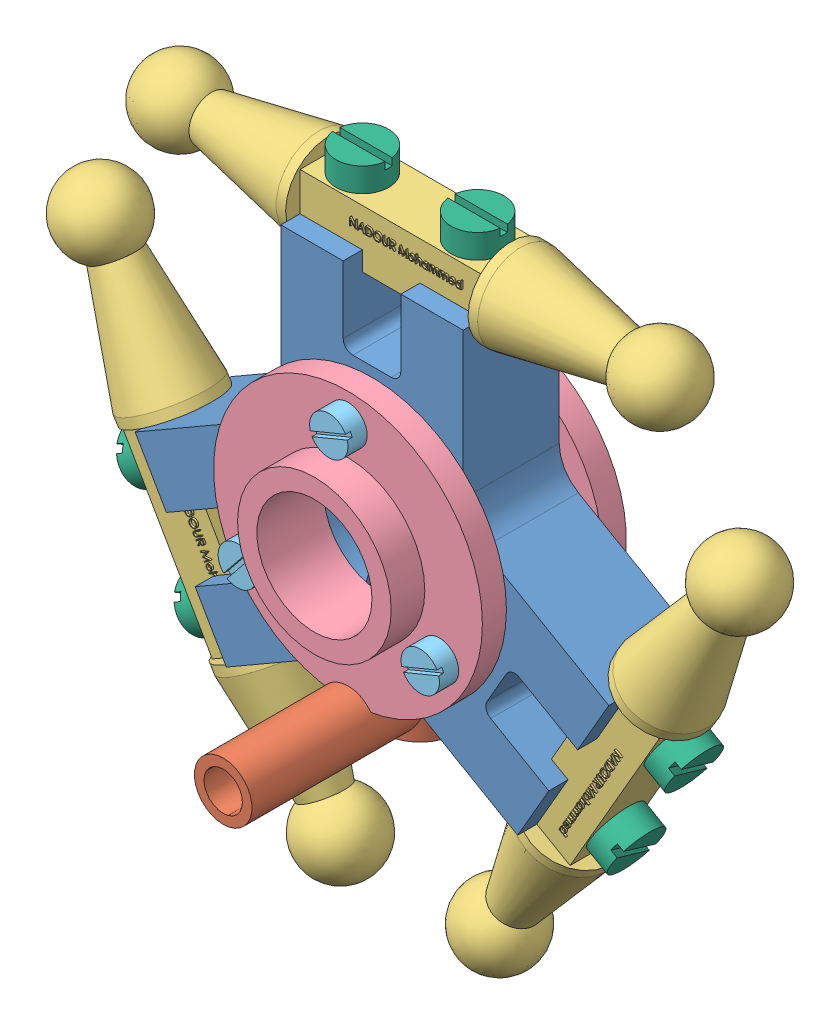
SolidWorks assembly Nacelle1, configuration Défaut. Lengths in mm.
Overall size (78.36 68.86 31.5).
19 component instances, 6 part files, 41 mates.
Components (placement in the parent):
- Pièce5_Nacelle-1: Pièce5_Nacelle [Défaut] at origin size (49.34 42.73 10)
- Pièce5_RaccordTuyau-1: Pièce5_RaccordTuyau [Défaut] at (0 -16.5885 0) x (1 0 0) z (0 1 0) size (8 24.5 10)
- Pièce2_Articulation-1: Pièce2_Articulation [Défaut] at (0 24 0) size (58 9 9)
- Pièce2_Articulation-2: Pièce2_Articulation [Défaut] at (-20.7846 -12 0) x (0.5 -0.866025 0) z (0 0 1) size (58 9 9)
- Pièce2_Articulation-3: Pièce2_Articulation [Défaut] at (20.7846 -12 0) x (-0.5 -0.866025 0) z (0 0 1) size (58 9 9)
- Pièce5_Capot-1: Pièce5_Capot [Défaut] at (0 0 11) x (-1 0 0) z (0 0 -1) size (28 28 7)
- Pièce5_Capot-2: Pièce5_Capot [Défaut] at (0 0 -11) size (28 28 7)
- Pièce5_ViceTcyM2.5_10-4: Pièce5_ViceTcyM2.5_10 [Défaut] at (0 11 -9.5) size (4 4 9.5)
- Pièce5_ViceTcyM2.5_10-5: Pièce5_ViceTcyM2.5_10 [Défaut] at (-9.5263 -5.5 -9.5) size (4 4 9.5)
- Pièce5_ViceTcyM2.5_10-6: Pièce5_ViceTcyM2.5_10 [Défaut] at (9.5263 -5.5 -9.5) size (4 4 9.5)
- Pièce5_ViceTcyM3_10-1: Pièce5_ViceTcyM3_10 [Défaut] at (-6 29.5 0) x (1 0 0) z (0 -1 0) size (5.5 5.5 12.5)
- Pièce5_ViceTcyM3_10-2: Pièce5_ViceTcyM3_10 [Défaut] at (6 29.5 0) x (1 0 0) z (0 -1 0) size (5.5 5.5 12.5)
- Pièce5_ViceTcyM3_10-3: Pièce5_ViceTcyM3_10 [Défaut] at (28.5477 -9.5538 0) x (0.25 0.433013 0.866025) z (-0.866025 0.5 0) size (5.5 5.5 12.5)
- Pièce5_ViceTcyM3_10-4: Pièce5_ViceTcyM3_10 [Défaut] at (22.5477 -19.9462 0) x (0.25 0.433013 0.866025) z (-0.866025 0.5 0) size (5.5 5.5 12.5)
- Pièce5_ViceTcyM3_10-5: Pièce5_ViceTcyM3_10 [Défaut] at (-28.5477 -9.5538 0) x (0.25 -0.433013 -0.866025) z (0.866025 0.5 0) size (5.5 5.5 12.5)
- Pièce5_ViceTcyM3_10-6: Pièce5_ViceTcyM3_10 [Défaut] at (-22.5477 -19.9462 0) x (0.25 -0.433013 -0.866025) z (0.866025 0.5 0) size (5.5 5.5 12.5)
- Pièce5_ViceTcyM2.5_10-7: Pièce5_ViceTcyM2.5_10 [Défaut] at (9.5263 -5.5 9.5) x (-0.923728 -0.383049 0) z (0 0 -1) size (4 4 9.5)
- Pièce5_ViceTcyM2.5_10-8: Pièce5_ViceTcyM2.5_10 [Défaut] at (0 11 9.5) x (-0.923728 -0.383049 0) z (0 0 -1) size (4 4 9.5)
- Pièce5_ViceTcyM2.5_10-9: Pièce5_ViceTcyM2.5_10 [Défaut] at (-9.5263 -5.5 9.5) x (-0.627519 -0.778601 0) z (0 0 -1) size (4 4 9.5)
Mates (geometry in assembly coordinates):
- Coaxiale1: concentric aligned: cylinder of Pièce5_Nacelle-1 through (0 -18 0) axis (0 1 0) radius 4; cylinder of Pièce5_RaccordTuyau-1 through (0 -18.5885 0) axis (0 1 0) radius 4
- Coaxiale5: concentric anti-aligned: cylinder of Pièce5_Nacelle-1 through (0 -15.5885 -5) axis (0 0 1) radius 4; cylinder of Pièce5_RaccordTuyau-1 through (0 -15.5885 20.5) axis (0 0 -1) radius 3
- Coaxiale6: concentric aligned: cylinder of Pièce5_Nacelle-1 through (-6 16 0) axis (0 1 0) radius 1; cylinder of Pièce2_Articulation-1 through (-6 17.5 0) axis (0 1 0) radius 1.6
- Coaxiale7: concentric aligned: cylinder of Pièce5_Nacelle-1 through (6 16 0) axis (0 1 0) radius 1; cylinder of Pièce2_Articulation-1 through (6 17.5 0) axis (0 1 0) radius 1.6
- Coïncidente1: coincident anti-aligned: plane of Pièce5_Nacelle-1 through (9.5 21 -3) normal (0 1 0); plane of Pièce2_Articulation-1 through (-9.5 21 -3) normal (0 -1 0)
- Coaxiale8: concentric anti-aligned: cylinder of Pièce5_Nacelle-1 through (-10.8564 -13.1962 0) axis (-0.866025 -0.5 0) radius 1; cylinder of Pièce2_Articulation-2 through (-23.4138 -20.4462 0) axis (0.866025 0.5 0) radius 1.6
- Coaxiale9: concentric anti-aligned: cylinder of Pièce5_Nacelle-1 through (-16.8564 -2.8038 0) axis (-0.866025 -0.5 0) radius 1; cylinder of Pièce2_Articulation-2 through (-29.4138 -10.0538 0) axis (0.866025 0.5 0) radius 1.6
- Coïncidente2: coincident anti-aligned: plane of Pièce5_Nacelle-1 through (-22.9365 -2.2728 -3) normal (-0.866025 -0.5 0); plane of Pièce2_Articulation-2 through (-22.9365 -2.2728 -3) normal (0.866025 0.5 0)
- Coaxiale10: concentric aligned: cylinder of Pièce5_Nacelle-1 through (10.8564 -13.1962 0) axis (0.866025 -0.5 0) radius 1; cylinder of Pièce2_Articulation-3 through (12.1554 -13.9462 0) axis (0.866025 -0.5 0) radius 1.6
- Coaxiale11: concentric aligned: cylinder of Pièce5_Nacelle-1 through (16.8564 -2.8038 0) axis (0.866025 -0.5 0) radius 1; cylinder of Pièce2_Articulation-3 through (18.1554 -3.5538 0) axis (0.866025 -0.5 0) radius 1.6
- Coïncidente3: coincident anti-aligned: plane of Pièce5_Nacelle-1 through (13.4365 -18.7272 -3) normal (0.866025 -0.5 0); plane of Pièce2_Articulation-3 through (22.9365 -2.2728 -3) normal (-0.866025 0.5 0)
- Coaxiale12: concentric aligned: cylinder of Pièce2_Articulation-1 through (6 17.5 0) axis (0 1 0) radius 1.6; cylinder of Pièce5_ViceTcyM3_10-2 through (6 17 0) axis (0 1 0) radius 1.5
- Coaxiale13: concentric aligned: cylinder of Pièce2_Articulation-1 through (-6 17.5 0) axis (0 1 0) radius 1.6; cylinder of Pièce5_ViceTcyM3_10-1 through (-6 17 0) axis (0 1 0) radius 1.5
- Coaxiale14: concentric aligned: cylinder of Pièce2_Articulation-3 through (18.1554 -3.5538 0) axis (0.866025 -0.5 0) radius 1.6; cylinder of Pièce5_ViceTcyM3_10-3 through (17.7224 -3.3038 0) axis (0.866025 -0.5 0) radius 1.5
- Coaxiale15: concentric aligned: cylinder of Pièce2_Articulation-3 through (12.1554 -13.9462 0) axis (0.866025 -0.5 0) radius 1.6; cylinder of Pièce5_ViceTcyM3_10-4 through (11.7224 -13.6962 0) axis (0.866025 -0.5 0) radius 1.5
- Coaxiale19: concentric aligned: cylinder of Pièce5_Capot-2 through (0 11 -3) axis (0 0 -1) radius 1.3; cylinder of Pièce5_ViceTcyM2.5_10-4 through (0 11 0) axis (0 0 -1) radius 1.3
- Coaxiale20: concentric aligned: cylinder of Pièce5_Capot-2 through (-9.5263 -5.5 -3) axis (0 0 -1) radius 1.3; cylinder of Pièce5_ViceTcyM2.5_10-5 through (-9.5263 -5.5 0) axis (0 0 -1) radius 1.3
- Coaxiale21: concentric aligned: cylinder of Pièce5_Capot-2 through (9.5263 -5.5 -3) axis (0 0 -1) radius 1.3; cylinder of Pièce5_ViceTcyM2.5_10-6 through (9.5263 -5.5 0) axis (0 0 -1) radius 1.3
- Coaxiale22: concentric anti-aligned: cylinder of Pièce2_Articulation-2 through (-29.4138 -10.0538 0) axis (0.866025 0.5 0) radius 1.6; cylinder of Pièce5_ViceTcyM3_10-5 through (-17.7224 -3.3038 0) axis (-0.866025 -0.5 0) radius 1.5
- Coaxiale23: concentric anti-aligned: cylinder of Pièce2_Articulation-2 through (-23.4138 -20.4462 0) axis (0.866025 0.5 0) radius 1.6; cylinder of Pièce5_ViceTcyM3_10-6 through (-11.7224 -13.6962 0) axis (-0.866025 -0.5 0) radius 1.5
- Coïncidente4: coincident anti-aligned: plane of Pièce2_Articulation-2 through (-28.1327 -5.2728 -3) normal (-0.866025 -0.5 0); plane of Pièce5_ViceTcyM3_10-5 through (-26.3827 -8.3038 0) normal (0.866025 0.5 0)
- Coïncidente5: coincident anti-aligned: plane of Pièce2_Articulation-2 through (-28.1327 -5.2728 -3) normal (-0.866025 -0.5 0); plane of Pièce5_ViceTcyM3_10-6 through (-20.3827 -18.6962 0) normal (0.866025 0.5 0)
- Coïncidente9: coincident anti-aligned: plane of Pièce2_Articulation-1 through (-9.5 27 -3) normal (0 1 0); plane of Pièce5_ViceTcyM3_10-1 through (-6 27 0) normal (0 -1 0)
- Coïncidente10: coincident anti-aligned: plane of Pièce2_Articulation-1 through (-9.5 27 -3) normal (0 1 0); plane of Pièce5_ViceTcyM3_10-2 through (6 27 0) normal (0 -1 0)
- Coïncidente11: coincident anti-aligned: plane of Pièce2_Articulation-3 through (28.1327 -5.2728 -3) normal (0.866025 -0.5 0); plane of Pièce5_ViceTcyM3_10-3 through (26.3827 -8.3038 0) normal (-0.866025 0.5 0)
- Coïncidente12: coincident anti-aligned: plane of Pièce2_Articulation-3 through (28.1327 -5.2728 -3) normal (0.866025 -0.5 0); plane of Pièce5_ViceTcyM3_10-4 through (20.3827 -18.6962 0) normal (-0.866025 0.5 0)
- Coïncidente13: coincident anti-aligned: plane of Pièce5_Capot-2 through (0 0 -7.5) normal (0 0 -1); plane of Pièce5_ViceTcyM2.5_10-4 through (0 11 -7.5) normal (0 0 1)
- Coïncidente14: coincident anti-aligned: plane of Pièce5_Capot-2 through (0 0 -7.5) normal (0 0 -1); plane of Pièce5_ViceTcyM2.5_10-5 through (-9.5263 -5.5 -7.5) normal (0 0 1)
- Coïncidente15: coincident anti-aligned: plane of Pièce5_Capot-2 through (0 0 -7.5) normal (0 0 -1); plane of Pièce5_ViceTcyM2.5_10-6 through (9.5263 -5.5 -7.5) normal (0 0 1)
- Coaxiale25: concentric anti-aligned: cylinder of Pièce5_Nacelle-1 through (0 0 -5) axis (0 0 1) radius 8; cylinder of Pièce5_Capot-2 through (0 0 -4) axis (0 0 -1) radius 6
- Coaxiale26: concentric anti-aligned: cylinder of Pièce5_Nacelle-1 through (0 11 -5) axis (0 0 1) radius 1.25; cylinder of Pièce5_ViceTcyM2.5_10-4 through (0 11 0) axis (0 0 -1) radius 1.3
- Coïncidente16: coincident anti-aligned: plane of Pièce5_Nacelle-1 through (0 0 -5) normal (0 0 -1); plane of Pièce5_Capot-2 through (0 0 -5) normal (0 0 1)
- Coïncidente17: coincident anti-aligned: plane of Pièce5_Nacelle-1 through (0 0 5) normal (0 0 1); plane of Pièce5_Capot-1 through (0 0 5) normal (0 0 -1)
- Coaxiale27: concentric aligned: cylinder of Pièce5_Nacelle-1 through (0 0 -5) axis (0 0 1) radius 8; cylinder of Pièce5_Capot-1 through (0 0 4) axis (0 0 1) radius 6
- Coaxiale28: concentric aligned: cylinder of Pièce5_Nacelle-1 through (-9.5263 -5.5 -5) axis (0 0 1) radius 1.25; cylinder of Pièce5_Capot-1 through (-9.5263 -5.5 3) axis (0 0 1) radius 1.3
- Coïncidente18: coincident anti-aligned: circle of Pièce5_Capot-1; cylinder of Pièce5_ViceTcyM2.5_10-9 through (-9.5263 -5.5 0) axis (0 0 1) radius 1.3
- Coaxiale29: concentric aligned: cylinder of Pièce5_Capot-1 through (0 11 3) axis (0 0 1) radius 1.3; cylinder of Pièce5_ViceTcyM2.5_10-8 through (0 11 0) axis (0 0 1) radius 1.3
- Coaxiale30: concentric aligned: cylinder of Pièce5_Capot-1 through (9.5263 -5.5 3) axis (0 0 1) radius 1.3; cylinder of Pièce5_ViceTcyM2.5_10-7 through (9.5263 -5.5 0) axis (0 0 1) radius 1.3
- Coïncidente19: coincident anti-aligned: plane of Pièce5_Capot-1 through (0 0 7.5) normal (0 0 1); plane of Pièce5_ViceTcyM2.5_10-8 through (0 11 7.5) normal (0 0 -1)
- Coïncidente20: coincident anti-aligned: plane of Pièce5_Capot-1 through (0 0 7.5) normal (0 0 1); plane of Pièce5_ViceTcyM2.5_10-9 through (-9.5263 -5.5 7.5) normal (0 0 -1)
- Coïncidente21: coincident anti-aligned: plane of Pièce5_Capot-1 through (0 0 7.5) normal (0 0 1); plane of Pièce5_ViceTcyM2.5_10-7 through (9.5263 -5.5 7.5) normal (0 0 -1)
